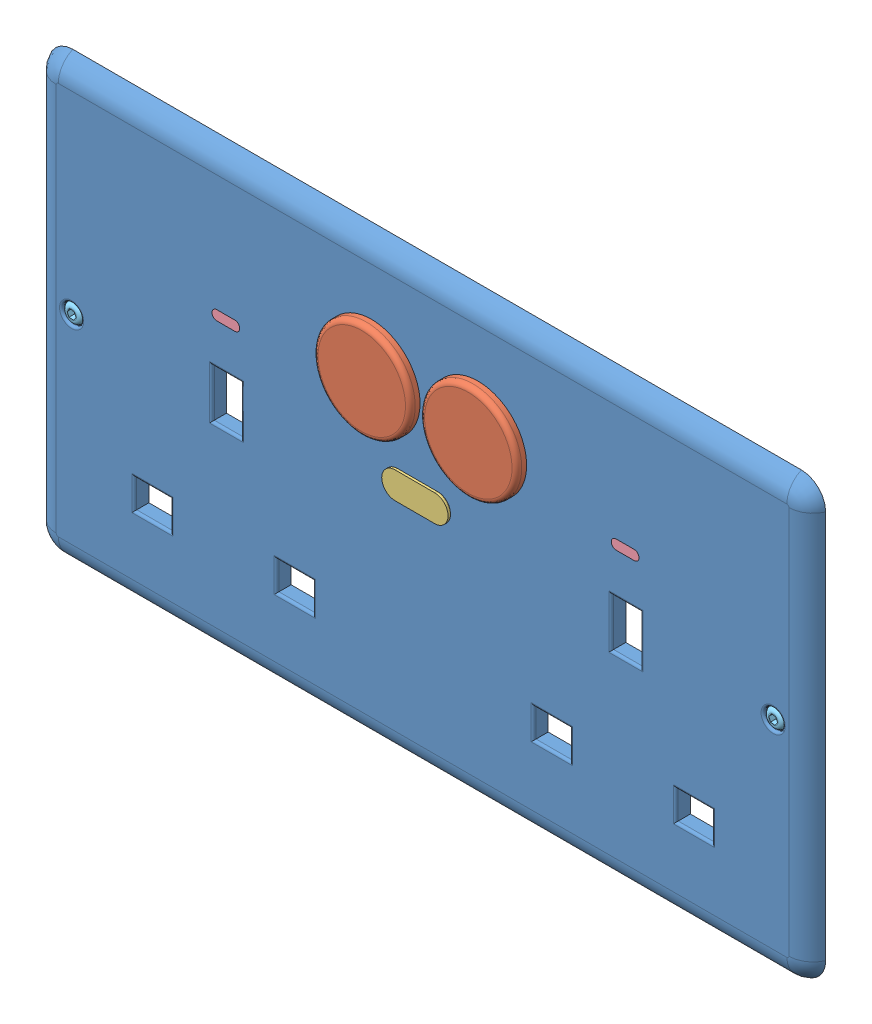
SolidWorks assembly TwoSwitchAss, configuration Default. Lengths in mm.
Overall size (160 90 5).
8 component instances, 5 part files, 18 mates.
Components (placement in the parent):
- TwoSwitch-1: TwoSwitch [Default] at (16.0741 68.0332 5.2788) size (160 90 3)
- Button20mm-1: Button20mm [Default] at (-15.6841 11.1968 5.2788) x (0.997139 -0.075589 0) z (0 0 1) size (20 20 5)
- CoverFilter-1: CoverFilter [Default] at (25.8771 11.0554 8.2788) size (13.66 5.5 0.5)
- LEDindicator-1: LEDindicator [Default] at (-30.825 32.0128 5.2788) size (5.72 2 3)
- Screw4mm-1: Screw4mm [Default] at (-86.2235 7.1881 8.2788) x (0.582967 0.812496 0) z (0 0 -1) size (4 4 3)
- Button20mm-2: Button20mm [Default] at (4.8754 10.0426 5.2788) x (0.982053 -0.188605 0) z (0 0 1) size (20 20 5)
- LEDindicator-2: LEDindicator [Default] at (51.3794 32.2403 5.2788) size (5.72 2 3)
- Screw4mm-2: Screw4mm [Default] at (58.3055 7.1525 8.2788) x (0.600574 0.79957 0) z (0 0 -1) size (4 4 3)
Mates (geometry in assembly coordinates):
- Concentric1: concentric anti-aligned: cylinder of TwoSwitch-1 through (-26.0726 22.6921 5.2788) axis (0 0 1) radius 10; cylinder of Button20mm-1 through (-26.0726 22.6921 10.2788) axis (0 0 -1) radius 10
- Concentric2: concentric anti-aligned: cylinder of TwoSwitch-1 through (-4.1371 22.6458 5.2788) axis (0 0 1) radius 10; cylinder of Button20mm-2 through (-4.1371 22.6458 10.2788) axis (0 0 -1) radius 10
- Coincident1: coincident anti-aligned: plane of TwoSwitch-1 through (-57.9014 18.4932 5.2788) normal (0 -1 0); plane of LEDindicator-1 through (-57.9014 18.4932 8.2788) normal (0 1 0)
- Coincident2: coincident anti-aligned: plane of TwoSwitch-1 through (24.3031 16.7207 5.2788) normal (0 1 0); plane of LEDindicator-2 through (24.3031 16.7207 8.2788) normal (0 -1 0)
- Coincident3: coincident aligned: circle of TwoSwitch-1; circle of LEDindicator-2
- Coincident4: coincident aligned: circle of TwoSwitch-1; circle of LEDindicator-1
- Concentric3: concentric: cylinder of TwoSwitch-1 through (-87.8045 2.6921 5.2788) axis (0 0 1) radius 2; cylinder of Screw4mm-1 through (-87.8045 2.6921 5.2788) axis (0 0 1) radius 2
- Concentric4: concentric: cylinder of TwoSwitch-1 through (56.6267 2.6921 5.2788) axis (0 0 1) radius 2; cylinder of Screw4mm-2 through (56.6267 2.6921 5.2788) axis (0 0 1) radius 2
- Coincident7: coincident aligned: line of TwoSwitch-1 through (-12.3151 8.7777 8.2788) axis (-1 0 0); line of CoverFilter-1 through (-12.5537 8.7777 8.2788) axis (-1 0 0)
- Parallel1: parallel aligned: line of TwoSwitch-1 through (-18.9019 3.7777 8.2788) axis (1 0 0); line of CoverFilter-1 through (-20.709 3.2777 8.2788) axis (1 0 0)
- Parallel2: parallel aligned: line of TwoSwitch-1 through (-18.9019 3.7777 8.2788) axis (1 0 0); line of CoverFilter-1 through (-20.709 3.2777 8.2788) axis (1 0 0)
- Parallel3: parallel aligned: line of TwoSwitch-1 through (-18.9019 3.7777 8.2788) axis (1 0 0); line of CoverFilter-1 through (-20.709 3.2777 8.2788) axis (1 0 0)
- Coincident11: coincident: point of TwoSwitch-1; circle of CoverFilter-1
- Coincident12: coincident aligned: circle of TwoSwitch-1; circle of Button20mm-1
- Coincident13: coincident aligned: circle of TwoSwitch-1; circle of Button20mm-2
- Concentric5: concentric: circle of TwoSwitch-1; circle of Screw4mm-2
- Coincident14: coincident anti-aligned: circle of TwoSwitch-1; circle of Screw4mm-2
- Coincident15: coincident anti-aligned: circle of TwoSwitch-1; circle of Screw4mm-1
